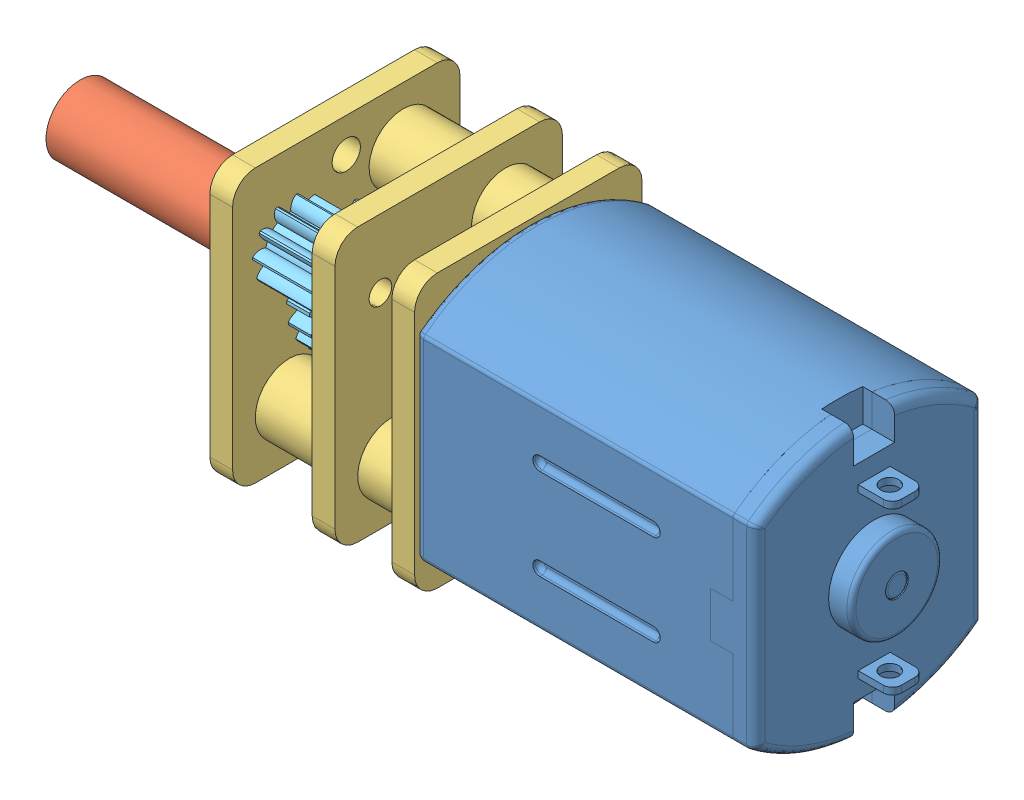
SolidWorks assembly n20 motor, configuration 轴长10mm. Lengths in mm.
Overall size (36.2 12.14 10.87).
11 component instances, 5 part files, 21 mates.
Components (placement in the parent):
- motor-1: motor [默认] at (-3.4114 0.0905 -5.0483)
- n20_shaft-1: n20_shaft [10mm] at (-13.1114 0.0905 -0.0483) x (0 -0.096252 -0.995357) z (0 0.995357 -0.096252) size (3 12 3)
- n20_gearbox-1: n20_gearbox [默认] at (-11.4114 0.0905 -0.0483) x (0 1 0) z (-1 0 0)
- cross recessed countersunk head screws gb1-1: cross recessed countersunk head screws gb1 [GB_CROSS_SCREWS_TYPE4 M1.6X3-2  H type-N] at (-12.4614 -3.4095 2.4517)
- cross recessed countersunk head screws gb1-2: cross recessed countersunk head screws gb1 [GB_CROSS_SCREWS_TYPE4 M1.6X3-2  H type-N] at (-12.4614 3.5905 -2.5483) x (1 0 0) z (0 0.116872 0.993147)
- spur gear_gb-1: spur gear_gb [GB - Spur gear 0.25M 10T 20PA 2FW ---S10A75H50L1.0N] at (-8.4114 -2.9095 -2.5483) x (1 0 0) z (0 -0.845955 0.533254)
- spur gear_gb-2: spur gear_gb [GB - Spur gear 0.25M 10T 20PA 2FW ---S10A75H50L1.0N] at (-4.4114 0.0905 -0.0483) x (-1 0 0) z (0 0.404067 -0.914729)
- spur gear_gb-4: spur gear_gb [GB - Spur gear 0.25M 16T 20PA 2FW ---S16A75H50L1.0N] at (-6.4114 -2.9095 -2.5483) x (1 0 0) z (0 -0.712706 0.701463)
- spur gear_gb-6: spur gear_gb [GB - Spur gear 0.25M 19T 20PA 2FW ---S19A75H50L1.0N] at (-9.9114 0.0905 -0.0483) x (1 0 0) z (0 0.321468 -0.94692)
- spur gear_gb-8: spur gear_gb [GB - Spur gear 0.25M 11T 20PA 3FW ---S11A75H50L1.0N] at (-10.9114 3.0905 2.9517) x (1 0 0) z (0 -0.604063 0.796937)
- spur gear_gb-10: spur gear_gb [GB - Spur gear 0.25M 19T 20PA 1FW ---S19A75H50L1.0N] at (-11.4114 0.0905 -0.0483) x (1 0 0) z (0 -0.330889 0.94367)
Mates (geometry in assembly coordinates):
- 同心1: concentric: cylinder of motor-1 through (-6.4114 0.0905 -0.0483) axis (1 0 0) radius 1; cylinder of n20_gearbox-1 through (-3.4114 0.0905 -0.0483) axis (-1 0 0) radius 0.5329
- 重合1: coincident: plane of motor-1 through (-3.4114 -5.9095 4.9517) normal (-1 0 0); plane of n20_gearbox-1 through (-3.4114 0.0905 -0.0483) normal (1 0 0)
- 重合2: coincident: plane of motor-1 through (-3.4114 0.0905 4.9517) normal (0 0 1); plane of n20_gearbox-1 through (-3.4114 6.0905 4.9517) normal (0 0 1)
- 同心2: concentric: cylinder of n20_shaft-1 through (-23.1114 0.0905 -0.0483) axis (1 0 0) radius 1.5; cylinder of n20_gearbox-1 through (-12.4114 0.0905 -0.0483) axis (1 0 0) radius 1.5
- 同心3: concentric: cylinder of n20_gearbox-1 through (-7.9114 3.5905 -2.5483) axis (-1 0 0) radius 0.9; cone of cross recessed countersunk head screws gb1-2 through (-11.4614 3.5905 -2.5483) axis (1 0 0)
- 重合4: coincident: cone of n20_gearbox-1 through (-12.4114 3.5905 -2.5483) axis (1 0 0); cone of cross recessed countersunk head screws gb1-2 through (-11.4614 3.5905 -2.5483) axis (1 0 0)
- 同心8: concentric: cylinder of n20_gearbox-1 through (-7.9114 -3.4095 2.4517) axis (-1 0 0) radius 0.9; cylinder of cross recessed countersunk head screws gb1-1 through (-7.9456 -3.4095 2.4517) axis (1 0 0) radius 0.8
- 重合5: coincident: cone of n20_gearbox-1 through (-12.4114 -3.4095 2.4517) axis (1 0 0); cone of cross recessed countersunk head screws gb1-1 through (-11.4614 -3.4095 2.4517) axis (1 0 0)
- 同心10: concentric: cylinder of motor-1 through (-6.4114 0.0905 -0.0483) axis (1 0 0) radius 1; cylinder of spur gear_gb-2 through (-54.4115 0.0905 -0.0483) axis (1 0 0) radius 0.5
- 同心11: concentric: cylinder of n20_gearbox-1 through (-3.4114 -2.9095 -2.5483) axis (-1 0 0) radius 0.5; cylinder of spur gear_gb-4 through (43.5886 -2.9095 -2.5483) axis (-1 0 0) radius 0.5
- 重合6: coincident: plane of n20_gearbox-1 through (-4.4114 0.0905 -0.0483) normal (-1 0 0); plane of spur gear_gb-4 through (-4.4114 -2.9095 -2.5483) normal (1 0 0)
- 同心12: concentric: cylinder of n20_gearbox-1 through (-6.9114 0.0905 -0.0483) axis (-1 0 0) radius 0.5; cylinder of spur gear_gb-6 through (40.0886 0.0905 -0.0483) axis (-1 0 0) radius 0.5
- 重合7: coincident: plane of n20_gearbox-1 through (-7.9114 0.0905 -0.0483) normal (-1 0 0); plane of spur gear_gb-6 through (-7.9114 0.0905 -0.0483) normal (1 0 0)
- 同心13: concentric: cylinder of spur gear_gb-1 through (41.5886 -2.9095 -2.5483) axis (-1 0 0) radius 0.5; cylinder of spur gear_gb-4 through (43.5886 -2.9095 -2.5483) axis (-1 0 0) radius 0.5
- 重合8: coincident: plane of spur gear_gb-1 through (-6.4114 -2.9095 -2.5483) normal (1 0 0); plane of spur gear_gb-4 through (-6.4114 -2.9095 -2.5483) normal (-1 0 0)
- 同心14: concentric: cylinder of n20_gearbox-1 through (-6.9114 3.0905 2.9517) axis (-1 0 0) radius 0.5; cylinder of spur gear_gb-8 through (39.0886 3.0905 2.9517) axis (-1 0 0) radius 0.5
- 同心15: concentric: cylinder of spur gear_gb-6 through (40.0886 0.0905 -0.0483) axis (-1 0 0) radius 0.5; cylinder of spur gear_gb-10 through (38.5886 0.0905 -0.0483) axis (-1 0 0) radius 0.5
- 重合9: coincident: plane of n20_gearbox-1 through (-7.9114 0.0905 -0.0483) normal (-1 0 0); plane of spur gear_gb-8 through (-7.9114 3.0905 2.9517) normal (1 0 0)
- 重合10: coincident: plane of n20_gearbox-1 through (-11.4114 0.0905 -0.0483) normal (1 0 0); plane of spur gear_gb-10 through (-11.4114 0.0905 -0.0483) normal (-1 0 0)
- 重合11: coincident: plane of n20_gearbox-1 through (-4.4114 0.0905 -0.0483) normal (-1 0 0); plane of spur gear_gb-2 through (-4.4114 0.0905 -0.0483) normal (1 0 0)
- Coincident2: coincident: plane of n20_shaft-1 through (-13.1114 0.0905 -0.0483) normal (-1 0 0); plane of n20_gearbox-1 through (-13.1114 0.0905 -0.0483) normal (-1 0 0)
